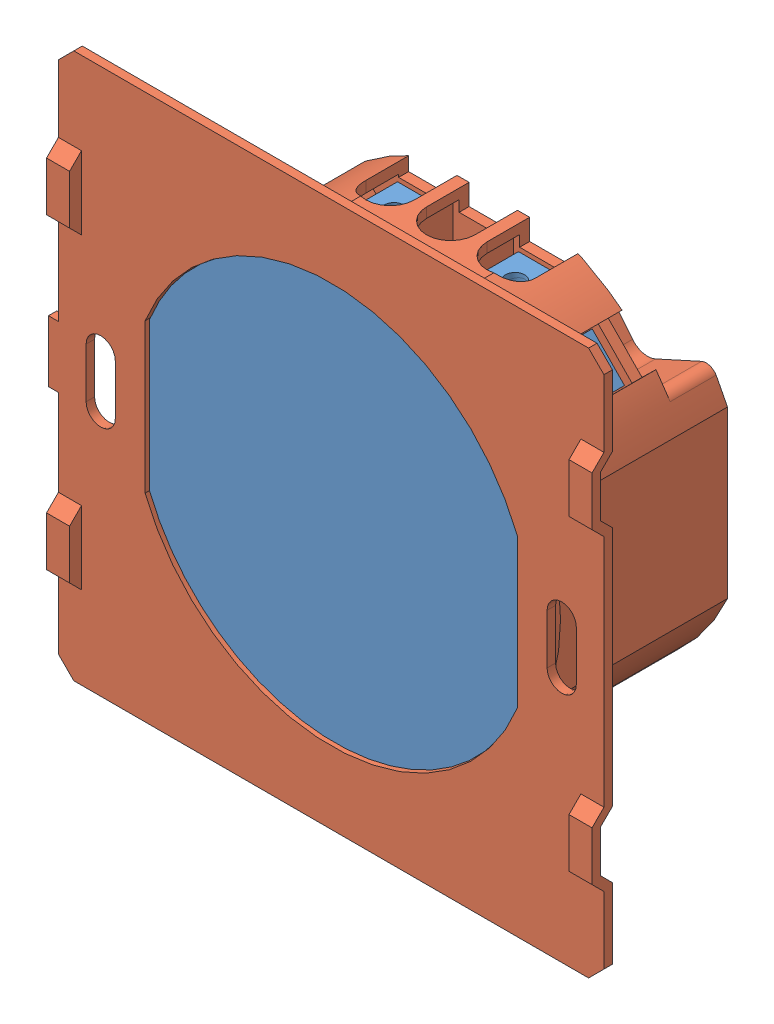
SolidWorks assembly Assem4, configuration Default. Lengths in mm.
Overall size (72.3 71 28.65).
2 component instances, 2 part files, 6 mates.
Components (placement in the parent):
- pcb-1: pcb [Default] at (0 0 -8.4) size (48.25 52 24.5)
- casing-1: casing [Default] at origin size (72.3 71 28.65)
Mates (geometry in assembly coordinates):
- InPlace1: in place: plane of casing-1 through (0 0 0) normal (0 0 1); moOrthogonalPlaneRef_w of casing-1 through (0 0 0) normal (0 1 0); plane of casing-1 through (0 0 0) normal (1 0 0); unknown of casing-1
- Coincident1: coincident aligned: plane of casing-1; plane of assembly
- Coincident2: coincident aligned: plane of casing-1 through (0 0 0) normal (0 1 0); moOrthogonalPlaneRef_w of assembly
- Coincident3: coincident anti-aligned: plane of casing-1 through (0 0 0) normal (1 0 0); moOrthogonalPlaneRef_w of assembly
- Distance2: distance = 7.5 mm: plane of pcb-1 through (-7.875 18.8103 -19.3) normal (0 0 -1); plane of casing-1 through (0 0 -26.8) normal (0 0 -1)
- Distance3: distance = 0.5 mm aligned: plane of pcb-1 through (0 0 0.6) normal (0 0 1); plane of casing-1 through (0 0 1.1) normal (0 0 1)
